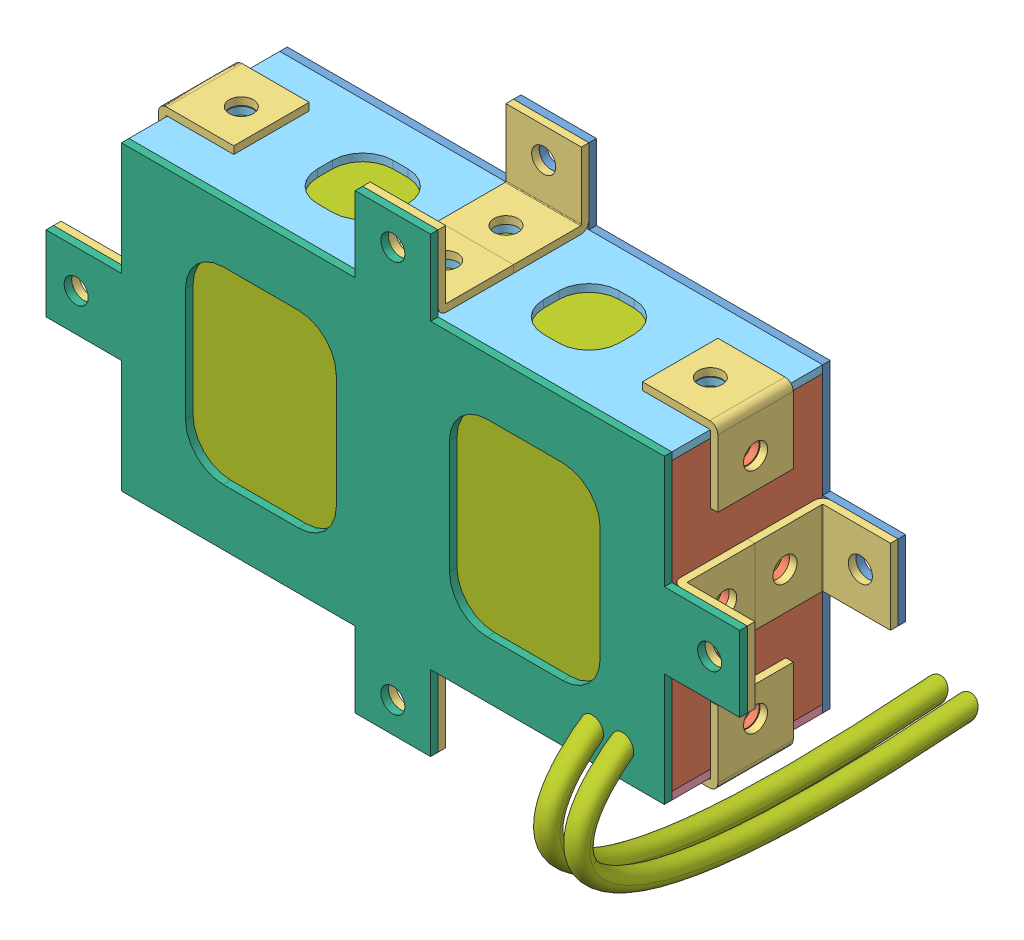
SolidWorks assembly assembly_5V, configuration Default. Lengths in mm.
Overall size (92 66.86 53.62).
19 component instances, 7 part files, 0 mates.
Components (placement in the parent):
- battery_box_5V_base-1: battery_box_5V_base [Default] at origin size (92 60 1)
- battery_box_5V_side1-1: battery_box_5V_side1 [Default] at (35 0 11) x (0 1 0) z (1 0 0) size (38 20 1)
- connector-1: connector [Default] at (41 0 1) x (0 -1 0) z (0 0 1) size (10 10 10)
- connector-2: connector [Default] at (-41 0 1) x (0 1 0) z (0 0 1) size (10 10 10)
- connector-3: connector [Default] at (36 0 16) x (0 -1 0) z (1 0 0) size (10 10 10)
- battery_box_5V_side1-2: battery_box_5V_side1 [Default] at (-36 0 11) x (0 1 0) z (1 0 0) size (38 20 1)
- battery_box_5V_front-1: battery_box_5V_front [Default] at (0 -19 11) x (1 0 0) z (0 -1 0) size (72 20 1)
- connector-4: connector [Default] at (-41 0 21) x (0 -1 0) z (0 0 -1) size (10 10 10)
- connector-5: connector [Default] at (0 25 1) size (10 10 10)
- connector-6: connector [Default] at (0 -25 21) x (1 0 0) z (0 0 -1) size (10 10 10)
- connector-7: connector [Default] at (0 -25 1) x (-1 0 0) z (0 0 1) size (10 10 10)
- connector-8: connector [Default] at (32.1 -21.1 11) x (0 0 -1) z (0 1 0) size (10 10 10)
- battery_box_5V_back-1: battery_box_5V_back [Default] at (0 19 11) x (1 0 0) z (0 1 0) size (72 20 1)
- battery_box_5V_top-1: battery_box_5V_top [Default] at (0 0 21) size (92 60 1)
- connector-9: connector [Default] at (0 25 21) x (-1 0 0) z (0 0 -1) size (10 10 10)
- connector-10: connector [Default] at (-37.1 16.1 11) x (0 0 1) z (1 0 0) size (10 10 10)
- connector-11: connector [Default] at (37.1 16.1 11) x (0 0 -1) z (-1 0 0) size (10 10 10)
- connector-12: connector [Default] at (-32.1 -21.1 11) x (0 0 1) z (0 1 0) size (10 10 10)
- battery_5V-1: battery_5V [Default] at (0 0 1) size (70 55.86 53.62)
